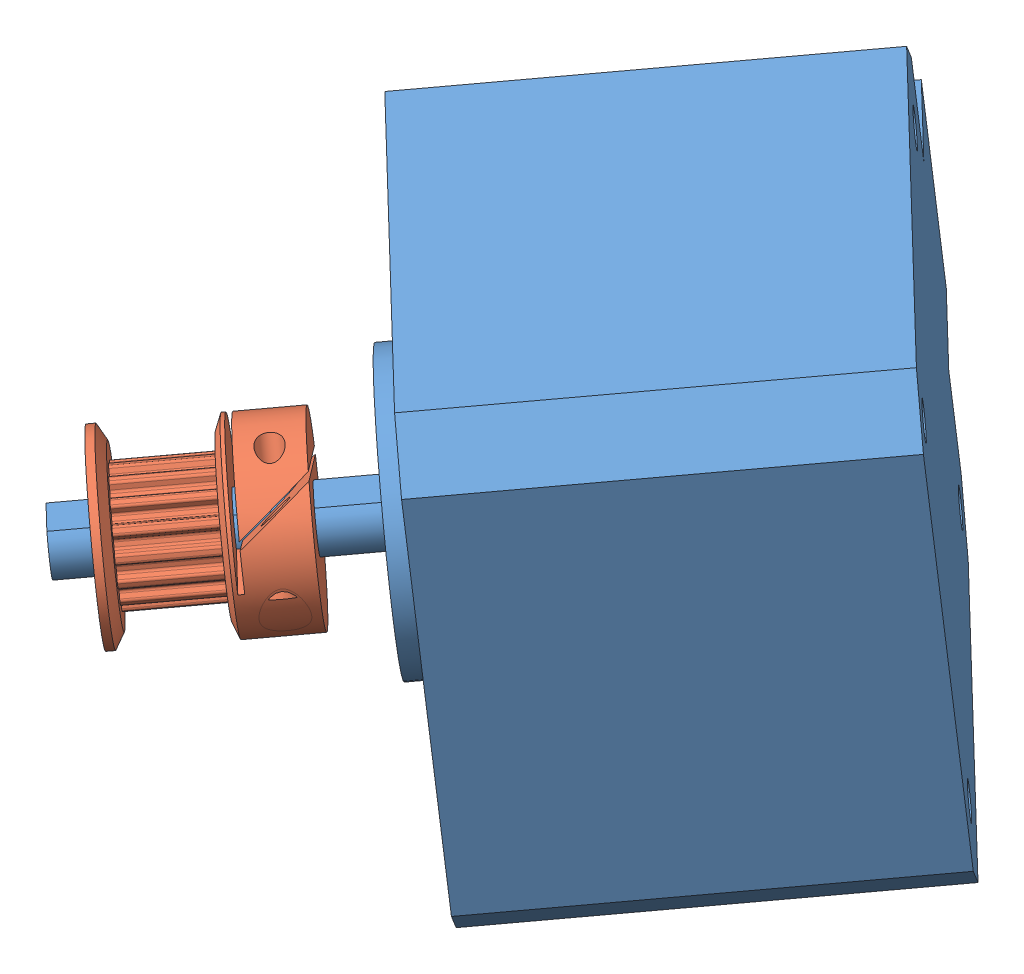
SolidWorks assembly motor-with-pulley, configuration Default. Lengths in mm.
Overall size (78.14 49.22 80.4).
2 component instances, 2 part files, 2 mates.
Components (placement in the parent):
- 408-1: 408 [Default] at (33.5099 6.4299 11.1332) x (0.719549 -0.038441 0.693377) z (-0.693377 -0.095039 0.71428) size (50.7 42 57.75)
- 782-1: 782 [Default] at (1.3025 2.0154 44.3115) x (0.603928 0.464075 0.648001) z (0.693377 0.095039 -0.71428) size (14.7 14.7 14.3)
Mates (geometry in assembly coordinates):
- Concentric15: concentric anti-aligned: cylinder of 408-1 through (-6.5326 0.9414 52.3829) axis (0.693377 0.095039 -0.71428) radius 2.5; cylinder of 782-1 through (5.6708 2.6141 39.8115) axis (-0.693377 -0.095039 0.71428) radius 2.5
- Distance4: distance = 3 mm aligned: plane of 408-1 through (-6.5326 0.9414 52.3829) normal (-0.693377 -0.095039 0.71428); plane of 782-1 through (-4.4525 1.2266 50.24) normal (-0.693377 -0.095039 0.71428)
